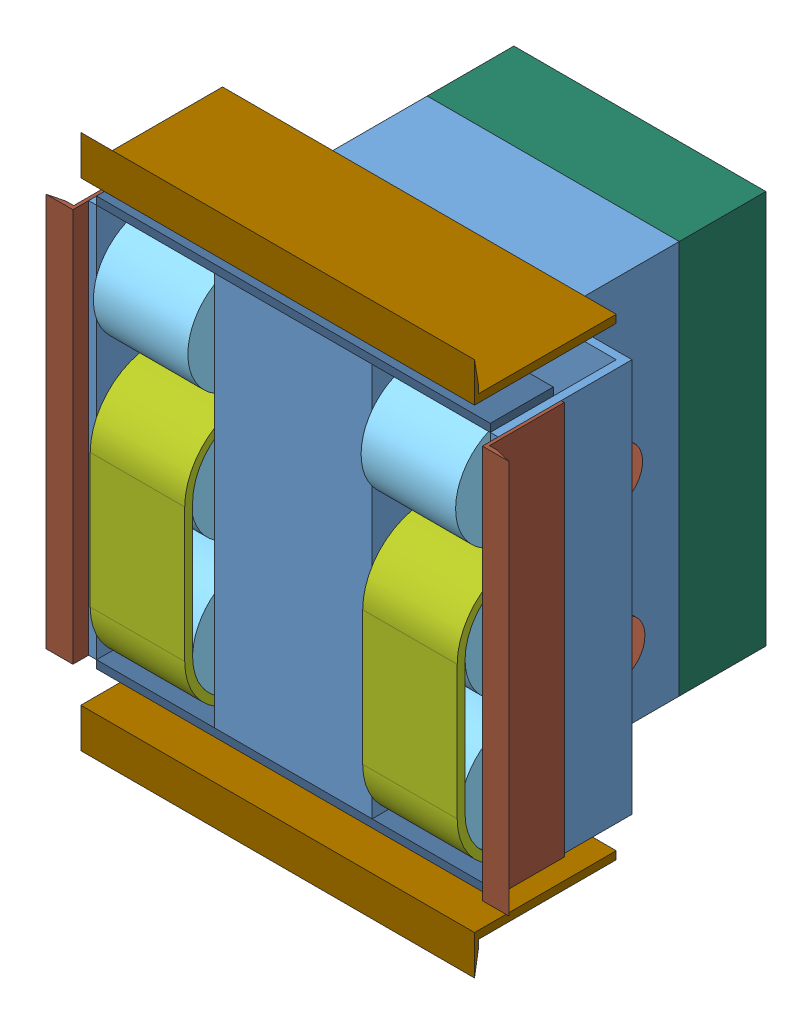
SolidWorks assembly Assemblage2, configuration Défaut. Lengths in mm.
Overall size (294 340 241.57).
35 component instances, 15 part files, 84 mates.
Components (placement in the parent):
- CHASSIS INFERIEUR-1: CHASSIS INFERIEUR [Défaut] at (41.3678 -114.8816 337.5001) size (260 250 165)
- verin-1: verin [Défaut] at (55.5971 35.1184 227.5001) x (0 0 1) z (-1 0 0) size (40 40 135)
- verin-2: verin [Défaut] at (-64.1633 -14.8816 227.5001) x (0 1 0) z (1 0 0) size (40 40 135)
- verin-3: verin [Défaut] at (-62.8283 80.1184 227.5001) x (0 0 -1) z (1 0 0) size (40 40 135)
- verin-4: verin [Défaut] at (57.0896 -59.8816 227.5001) x (0 -1 0) z (-1 0 0) size (40 40 135)
- moteur dc-1: moteur dc [Défaut] at (-28.1322 -92.8521 294.8582) x (-1 0 0) z (0 0.999096 -0.042505) size (44 72 145.16)
- moteur dc-2: moteur dc [Défaut] at (20.8678 112.6401 292.734) x (1 0 0) z (0 -0.999761 -0.021843) size (44 72 145.16)
- axe moteur2-1: axe moteur2 [Défaut] at (-35.6322 10.1184 315.5001) x (0 -0.257747 0.966212) z (-1 0 0) size (15 15 90)
- axe moteur2-2: axe moteur2 [Défaut] at (28.3678 10.1184 315.5001) x (0 -0.997153 0.07541) z (1 0 0) size (15 15 90)
- roue70-1: roue70 [Défaut] at (53.3678 10.1184 315.5001) x (0 0 -1) z (1 0 0) size (70 70 60)
- roue70-2: roue70 [Défaut] at (-60.6322 10.1184 315.5001) x (0 0 1) z (-1 0 0) size (70 70 60)
- axe roues-1: axe roues [Défaut] at (110.3678 -74.8816 315.5001) x (0 0.810625 0.585565) z (-1 0 0) size (15.31 15.16 240)
- roue70-3: roue70 [Défaut] at (-59.6322 -74.8816 315.5001) x (0 0 1) z (-1 0 0) size (70 70 60)
- roue70-4: roue70 [Défaut] at (110.3678 -74.8816 315.5001) x (0 -0.558004 0.829838) z (-1 0 0) size (70 70 60)
- roue70-5: roue70 [Défaut] at (-117.6322 95.1184 320.5001) x (0 0 -1) z (1 0 0) size (70 70 60)
- roue70-6: roue70 [Défaut] at (52.3678 95.1184 320.5001) x (0 -0.261804 -0.965121) z (1 0 0) size (70 70 60)
- axe roues-2: axe roues [Défaut] at (-117.6322 95.1184 320.5001) x (0 -0.953529 0.3013) z (1 0 0) size (15.31 15.16 240)
- courroie-1: courroie [Défaut] at (53.3678 -74.8816 315.5001) x (0 1 0) z (1 0 0) size (165 80 60)
- appuie pare-1: appuie pare [Défaut] at (46.3678 135.1184 297.5001) x (1 0 0) z (0 1 0) size (90 35 20)
- pare avant-1: pare avant [Défaut] at (121.3678 155.1184 352.5001) x (1 0 0) z (0 1 0) size (250 90 25)
- appuie pare-3: appuie pare [Défaut] at (46.3678 -114.8816 262.5001) x (1 0 0) z (0 -1 0) size (90 35 20)
- pare avant-3: pare avant [Défaut] at (-128.6322 -134.8816 352.5001) x (-1 0 0) z (0 -1 0) size (250 90 25)
- suport capteurs-1: suport capteurs [Défaut] at (121.3678 135.1184 342.5001) x (1 0 0) z (0 1 0) size (250 40 5)
- suport capteurs-2: suport capteurs [Défaut] at (121.3678 -119.8816 342.5001) x (1 0 0) z (0 1 0) size (250 40 5)
- pare coté-1: pare coté [Défaut] at (-133.6322 135.1184 352.5001) x (0 1 0) z (-1 0 0) size (250 50 17)
- pare coté-2: pare coté [Défaut] at (126.3678 -114.8816 352.5001) x (0 -1 0) z (1 0 0) size (250 50 17)
- courroie-2: courroie [Défaut] at (-119.6322 -74.8816 315.5001) x (0 1 0) z (1 0 0) size (165 80 60)
- appuie verin-1: appuie verin [Défaut] at (-53.6322 -109.8816 257.5001) x (0 -1 0) z (1 0 0) size (240 110 5)
- appuie verin-2: appuie verin [Défaut] at (46.3678 130.1184 257.5001) x (0 1 0) z (-1 0 0) size (240 110 5)
- chassis superieur-2: chassis superieur [Défaut] at (-83.6322 -114.8816 177.5001) x (-1 0 0) z (0 0 -1) size (160 250 55) (hidden)
- moteur verin-1: moteur verin [Défaut] at (71.3678 37.6184 175.0001) x (0 0.993394 -0.114755) z (-1 0 0) size (25 25 25)
- moteur verin-2: moteur verin [Défaut] at (-78.6322 -17.3816 175.0001) x (0 -0.999164 -0.040883) z (1 0 0) size (25 25 25)
- attache verin-1: attache verin [Défaut] at (-38.6322 -17.8816 174.8001) x (0 -0.190501 -0.981687) z (1 0 0) size (59.09 70.11 25)
- attache verin-2: attache verin [Défaut] at (31.3678 38.1184 174.8001) x (0 0.67748 -0.735541) z (-1 0 0) size (59.09 70.11 25)
- chassis superieur-3: chassis superieur [Défaut] at (-83.6322 -114.8816 177.5001) x (-1 0 0) z (0 0 -1) size (160 250 55)
Mates (geometry in assembly coordinates):
- Coaxiale1: concentric anti-aligned: cylinder of CHASSIS INFERIEUR-1 through (-3.6322 35.1184 227.5001) axis (1 0 0) radius 20; cylinder of verin-1 through (85.5971 35.1184 227.5001) axis (-1 0 0) radius 17.5
- Coaxiale2: concentric anti-aligned: cylinder of CHASSIS INFERIEUR-1 through (-3.6322 -59.8816 227.5001) axis (1 0 0) radius 20; cylinder of verin-4 through (87.0896 -59.8816 227.5001) axis (-1 0 0) radius 17.5
- Coaxiale3: concentric anti-aligned: cylinder of CHASSIS INFERIEUR-1 through (-73.6322 80.1184 227.5001) axis (-1 0 0) radius 20; cylinder of verin-3 through (-92.8283 80.1184 227.5001) axis (1 0 0) radius 17.5
- Coaxiale4: concentric anti-aligned: cylinder of CHASSIS INFERIEUR-1 through (-73.6322 -14.8816 227.5001) axis (-1 0 0) radius 20; cylinder of verin-2 through (-94.1633 -14.8816 227.5001) axis (1 0 0) radius 17.5
- Coïncidente1: coincident aligned: plane of verin-2 through (40.8367 -34.8816 207.5001) normal (0 0 -1); plane of verin-3 through (42.1717 100.1184 207.5001) normal (0 0 -1)
- Coïncidente2: coincident aligned: plane of verin-1 through (-49.4029 55.1184 207.5001) normal (0 0 -1); plane of verin-4 through (-47.9104 -39.8816 207.5001) normal (0 0 -1)
- Coaxiale5: concentric anti-aligned: cylinder of CHASSIS INFERIEUR-1 through (-48.6322 10.1184 315.5001) axis (-1 0 0) radius 10; cylinder of moteur dc-1 through (-45.6322 10.1184 315.5001) axis (1 0 0) radius 5.5
- Coïncidente3: coincident anti-aligned: plane of CHASSIS INFERIEUR-1 through (-48.6322 -114.8816 337.5001) normal (1 0 0); plane of moteur dc-1 through (-48.6322 20.345 298.0594) normal (-1 0 0)
- Coaxiale6: concentric anti-aligned: cylinder of CHASSIS INFERIEUR-1 through (41.3678 10.1184 315.5001) axis (1 0 0) radius 10; cylinder of moteur dc-2 through (38.3678 10.1184 315.5001) axis (-1 0 0) radius 5.5
- Coïncidente4: coincident anti-aligned: plane of CHASSIS INFERIEUR-1 through (41.3678 -114.8816 337.5001) normal (-1 0 0); plane of moteur dc-2 through (41.3678 30.3286 314.946) normal (1 0 0)
- Coaxiale7: concentric aligned: cylinder of moteur dc-1 through (-45.6322 10.1184 315.5001) axis (1 0 0) radius 5.5; cylinder of axe moteur2-1 through (-120.6322 10.1184 315.5001) axis (1 0 0) radius 5
- Coïncidente5: coincident anti-aligned: plane of moteur dc-1 through (-35.6322 -92.8521 294.8582) normal (-1 0 0); plane of axe moteur2-1 through (-35.6322 10.1184 315.5001) normal (1 0 0)
- Coaxiale8: concentric aligned: cylinder of moteur dc-2 through (38.3678 10.1184 315.5001) axis (-1 0 0) radius 5.5; cylinder of axe moteur2-2 through (113.3678 10.1184 315.5001) axis (-1 0 0) radius 5
- Coïncidente6: coincident anti-aligned: plane of moteur dc-2 through (28.3678 112.6401 292.734) normal (1 0 0); plane of axe moteur2-2 through (28.3678 10.1184 315.5001) normal (-1 0 0)
- Coaxiale9: concentric anti-aligned: cylinder of axe moteur2-2 through (113.3678 10.1184 315.5001) axis (-1 0 0) radius 5; cylinder of roue70-1 through (53.3678 10.1184 315.5001) axis (1 0 0) radius 5
- Coïncidente7: coincident anti-aligned: plane of axe moteur2-2 through (113.3678 10.1184 315.5001) normal (-1 0 0); plane of roue70-1 through (113.3678 10.1184 315.5001) normal (1 0 0)
- Coaxiale10: concentric anti-aligned: cylinder of axe moteur2-1 through (-120.6322 10.1184 315.5001) axis (1 0 0) radius 5; cylinder of roue70-2 through (-60.6322 10.1184 315.5001) axis (-1 0 0) radius 5
- Coïncidente8: coincident anti-aligned: plane of axe moteur2-1 through (-120.6322 10.1184 315.5001) normal (1 0 0); plane of roue70-2 through (-120.6322 10.1184 315.5001) normal (-1 0 0)
- Coaxiale11: concentric anti-aligned: cylinder of CHASSIS INFERIEUR-1 through (-48.6322 -74.8816 315.5001) axis (-1 0 0) radius 10; cylinder of axe roues-1 through (-119.6322 -74.8816 315.5001) axis (1 0 0) radius 5
- Distance1: distance = 1 mm anti-aligned: plane of axe roues-1 through (-54.6322 -74.8816 315.5001) normal (1 0 0); plane of CHASSIS INFERIEUR-1 through (-53.6322 -114.8816 337.5001) normal (-1 0 0)
- Coaxiale12: concentric anti-aligned: cylinder of axe roues-1 through (-119.6322 -74.8816 315.5001) axis (1 0 0) radius 5; cylinder of roue70-4 through (110.3678 -74.8816 315.5001) axis (-1 0 0) radius 5
- Coïncidente10: coincident anti-aligned: plane of axe roues-1 through (50.3678 -74.8816 315.5001) normal (1 0 0); plane of roue70-4 through (50.3678 -74.8816 315.5001) normal (-1 0 0)
- Coaxiale13: concentric anti-aligned: cylinder of axe roues-1 through (-119.6322 -74.8816 315.5001) axis (1 0 0) radius 5; cylinder of roue70-3 through (-59.6322 -74.8816 315.5001) axis (-1 0 0) radius 5
- Coïncidente11: coincident anti-aligned: plane of axe roues-1 through (-119.6322 -74.8816 315.5001) normal (1 0 0); plane of roue70-3 through (-119.6322 -74.8816 315.5001) normal (-1 0 0)
- Coaxiale14: concentric anti-aligned: cylinder of CHASSIS INFERIEUR-1 through (41.3678 95.1184 320.5001) axis (1 0 0) radius 10; cylinder of axe roues-2 through (112.3678 95.1184 320.5001) axis (-1 0 0) radius 5
- Distance3: distance = 1 mm anti-aligned: plane of axe roues-2 through (47.3678 95.1184 320.5001) normal (-1 0 0); plane of CHASSIS INFERIEUR-1 through (46.3678 -114.8816 337.5001) normal (1 0 0)
- Coaxiale15: concentric anti-aligned: cylinder of roue70-5 through (-117.6322 95.1184 320.5001) axis (1 0 0) radius 5; cylinder of axe roues-2 through (112.3678 95.1184 320.5001) axis (-1 0 0) radius 5
- Coïncidente14: coincident anti-aligned: plane of roue70-5 through (-117.6322 95.1184 320.5001) normal (-1 0 0); plane of axe roues-2 through (-117.6322 95.1184 320.5001) normal (1 0 0)
- Coaxiale16: concentric anti-aligned: cylinder of roue70-6 through (52.3678 95.1184 320.5001) axis (1 0 0) radius 5; cylinder of axe roues-2 through (112.3678 95.1184 320.5001) axis (-1 0 0) radius 5
- Coïncidente15: coincident anti-aligned: plane of roue70-6 through (52.3678 95.1184 320.5001) normal (-1 0 0); plane of axe roues-2 through (52.3678 95.1184 320.5001) normal (1 0 0)
- Coaxiale17: concentric anti-aligned: cylinder of roue70-4 through (50.3678 -74.8816 315.5001) axis (1 0 0) radius 35; cylinder of courroie-1 through (113.3678 -74.8816 315.5001) axis (-1 0 0) radius 35
- Coaxiale18: concentric aligned: cylinder of roue70-1 through (113.3678 10.1184 315.5001) axis (-1 0 0) radius 35; cylinder of courroie-1 through (113.3678 10.1184 315.5001) axis (-1 0 0) radius 35
- Coïncidente16: coincident aligned: plane of roue70-1 through (113.3678 10.1184 315.5001) normal (1 0 0); plane of courroie-1 through (113.3678 -74.8816 315.5001) normal (1 0 0)
- Coïncidente17: coincident anti-aligned: plane of CHASSIS INFERIEUR-1 through (41.3678 135.1184 342.5001) normal (0 1 0); plane of appuie pare-1 through (46.3678 135.1184 297.5001) normal (0 -1 0)
- Coïncidente18: coincident aligned: plane of CHASSIS INFERIEUR-1 through (46.3678 -114.8816 337.5001) normal (1 0 0); plane of appuie pare-1 through (46.3678 155.1184 297.5001) normal (1 0 0)
- Coïncidente19: coincident anti-aligned: plane of CHASSIS INFERIEUR-1 through (41.3678 -114.8816 262.5001) normal (0 0 1); plane of appuie pare-1 through (46.3678 155.1184 262.5001) normal (0 0 -1)
- Coïncidente20: coincident anti-aligned: plane of appuie pare-1 through (46.3678 155.1184 297.5001) normal (0 1 0); plane of pare avant-1 through (121.3678 155.1184 352.5001) normal (0 -1 0)
- Coïncidente21: coincident aligned: plane of appuie pare-1 through (46.3678 155.1184 262.5001) normal (0 0 -1); plane of pare avant-1 through (121.3678 160.1184 262.5001) normal (0 0 -1)
- Coïncidente22: coincident anti-aligned: plane of CHASSIS INFERIEUR-1 through (121.3678 -114.8816 337.5001) normal (-1 0 0); plane of pare avant-1 through (121.3678 160.1184 352.5001) normal (1 0 0)
- Coïncidente23: coincident anti-aligned: plane of CHASSIS INFERIEUR-1 through (41.3678 -114.8816 342.5001) normal (0 -1 0); plane of appuie pare-3 through (46.3678 -114.8816 262.5001) normal (0 1 0)
- Coïncidente24: coincident anti-aligned: plane of CHASSIS INFERIEUR-1 through (41.3678 -114.8816 262.5001) normal (0 0 1); plane of appuie pare-3 through (46.3678 -134.8816 262.5001) normal (0 0 -1)
- Coïncidente25: coincident aligned: plane of CHASSIS INFERIEUR-1 through (46.3678 -114.8816 337.5001) normal (1 0 0); plane of appuie pare-3 through (46.3678 -134.8816 262.5001) normal (1 0 0)
- Coïncidente26: coincident anti-aligned: plane of appuie pare-3 through (46.3678 -134.8816 262.5001) normal (0 -1 0); plane of pare avant-3 through (-128.6322 -134.8816 352.5001) normal (0 1 0)
- Coïncidente27: coincident aligned: plane of appuie pare-3 through (46.3678 -134.8816 262.5001) normal (0 0 -1); plane of pare avant-3 through (-128.6322 -139.8816 262.5001) normal (0 0 -1)
- Coïncidente28: coincident anti-aligned: plane of CHASSIS INFERIEUR-1 through (-128.6322 -114.8816 337.5001) normal (1 0 0); plane of pare avant-3 through (-128.6322 -139.8816 352.5001) normal (-1 0 0)
- Coïncidente29: coincident anti-aligned: plane of CHASSIS INFERIEUR-1 through (41.3678 135.1184 342.5001) normal (0 1 0); plane of suport capteurs-1 through (121.3678 135.1184 342.5001) normal (0 -1 0)
- Coïncidente30: coincident aligned: plane of CHASSIS INFERIEUR-1 through (41.3678 -114.8816 342.5001) normal (0 0 1); plane of suport capteurs-1 through (121.3678 140.1184 342.5001) normal (0 0 1)
- Coïncidente31: coincident aligned: plane of pare avant-1 through (121.3678 160.1184 352.5001) normal (1 0 0); plane of suport capteurs-1 through (121.3678 140.1184 342.5001) normal (1 0 0)
- Coïncidente32: coincident anti-aligned: plane of CHASSIS INFERIEUR-1 through (41.3678 -114.8816 342.5001) normal (0 -1 0); plane of suport capteurs-2 through (121.3678 -114.8816 342.5001) normal (0 1 0)
- Coïncidente33: coincident aligned: plane of pare avant-3 through (121.3678 -139.8816 352.5001) normal (1 0 0); plane of suport capteurs-2 through (121.3678 -114.8816 342.5001) normal (1 0 0)
- Coïncidente34: coincident aligned: plane of CHASSIS INFERIEUR-1 through (41.3678 -114.8816 342.5001) normal (0 0 1); plane of suport capteurs-2 through (121.3678 -114.8816 342.5001) normal (0 0 1)
- Coïncidente35: coincident anti-aligned: plane of CHASSIS INFERIEUR-1 through (126.3678 -114.8816 337.5001) normal (1 0 0); plane of pare coté-2 through (126.3678 -114.8816 352.5001) normal (-1 0 0)
- Coïncidente36: coincident aligned: plane of pare avant-1 through (121.3678 160.1184 352.5001) normal (0 0 1); plane of pare coté-2 through (128.3678 -114.8816 352.5001) normal (0 0 1)
- Coïncidente37: coincident aligned: plane of CHASSIS INFERIEUR-1 through (41.3678 -114.8816 342.5001) normal (0 -1 0); plane of pare coté-2 through (128.3678 -114.8816 352.5001) normal (0 -1 0)
- Coïncidente38: coincident anti-aligned: plane of CHASSIS INFERIEUR-1 through (-133.6322 -114.8816 337.5001) normal (-1 0 0); plane of pare coté-1 through (-133.6322 135.1184 352.5001) normal (1 0 0)
- Coïncidente39: coincident aligned: plane of pare avant-3 through (-128.6322 -139.8816 352.5001) normal (0 0 1); plane of pare coté-1 through (-135.6322 135.1184 352.5001) normal (0 0 1)
- Coïncidente40: coincident aligned: plane of CHASSIS INFERIEUR-1 through (41.3678 -114.8816 342.5001) normal (0 -1 0); plane of pare coté-1 through (-135.6322 -114.8816 352.5001) normal (0 -1 0)
- Coaxiale19: concentric anti-aligned: cylinder of roue70-2 through (-120.6322 10.1184 315.5001) axis (1 0 0) radius 35; cylinder of courroie-2 through (-59.6322 10.1184 315.5001) axis (-1 0 0) radius 35
- Coaxiale20: concentric anti-aligned: cylinder of roue70-3 through (-119.6322 -74.8816 315.5001) axis (1 0 0) radius 35; cylinder of courroie-2 through (-59.6322 -74.8816 315.5001) axis (-1 0 0) radius 35
- Coïncidente41: coincident aligned: plane of roue70-3 through (-119.6322 -74.8816 315.5001) normal (-1 0 0); plane of courroie-2 through (-119.6322 -74.8816 315.5001) normal (-1 0 0)
- Parallèle1: parallel anti-aligned: plane of CHASSIS INFERIEUR-1 through (-78.6322 135.1184 177.5001) normal (1 0 0); plane of appuie verin-1 through (-53.6322 -109.8816 257.5001) normal (-1 0 0)
- Coïncidente47: coincident anti-aligned: plane of CHASSIS INFERIEUR-1 through (41.3678 -109.8816 337.5001) normal (0 1 0); plane of appuie verin-1 through (-48.6322 -109.8816 257.5001) normal (0 -1 0)
- Parallèle3: parallel anti-aligned: plane of CHASSIS INFERIEUR-1 through (71.3678 135.1184 177.5001) normal (-1 0 0); plane of appuie verin-2 through (46.3678 130.1184 257.5001) normal (1 0 0)
- Coïncidente51: coincident anti-aligned: plane of CHASSIS INFERIEUR-1 through (41.3678 -109.8816 337.5001) normal (0 1 0); plane of appuie verin-2 through (41.3678 -109.8816 257.5001) normal (0 -1 0)
- Coïncidente52: coincident aligned: plane of CHASSIS INFERIEUR-1 through (41.3678 -114.8816 337.5001) normal (-1 0 0); plane of appuie verin-2 through (41.3678 130.1184 257.5001) normal (-1 0 0)
- Coïncidente53: coincident anti-aligned: plane of CHASSIS INFERIEUR-1 through (41.3678 -114.8816 257.5001) normal (0 0 -1); plane of appuie verin-2 through (41.3678 130.1184 257.5001) normal (0 0 1)
- Coïncidente56: coincident anti-aligned: plane of CHASSIS INFERIEUR-1 through (-48.6322 -114.8816 257.5001) normal (0 0 -1); plane of appuie verin-1 through (-48.6322 -109.8816 257.5001) normal (0 0 1)
- Coïncidente58: coincident anti-aligned: plane of CHASSIS INFERIEUR-1 through (41.3678 -114.8816 177.5001) normal (0 0 -1); plane of chassis superieur-2 through (-83.6322 -114.8816 177.5001) normal (0 0 1)
- Coïncidente59: coincident aligned: plane of CHASSIS INFERIEUR-1 through (76.3678 135.1184 177.5001) normal (1 0 0); plane of chassis superieur-2 through (76.3678 -114.8816 127.5001) normal (1 0 0)
- Coïncidente60: coincident aligned: plane of CHASSIS INFERIEUR-1 through (41.3678 -114.8816 342.5001) normal (0 -1 0); plane of chassis superieur-2 through (-83.6322 -114.8816 127.5001) normal (0 -1 0)
- Coïncidente61: coincident aligned: plane of CHASSIS INFERIEUR-1 through (-48.6322 -114.8816 337.5001) normal (1 0 0); plane of appuie verin-1 through (-48.6322 -109.8816 257.5001) normal (1 0 0)
- Coïncidente62: coincident anti-aligned: plane of CHASSIS INFERIEUR-1 through (-78.6322 135.1184 177.5001) normal (1 0 0); plane of moteur verin-2 through (-78.6322 -17.3816 175.0001) normal (-1 0 0)
- Coïncidente63: coincident anti-aligned: plane of CHASSIS INFERIEUR-1 through (71.3678 135.1184 177.5001) normal (-1 0 0); plane of moteur verin-1 through (71.3678 37.6184 175.0001) normal (1 0 0)
- Distance10: distance = 80 mm anti-aligned: cylinder of moteur verin-1 through (46.3678 37.6184 175.0001) axis (1 0 0) radius 12.5; plane of CHASSIS INFERIEUR-1 through (41.3678 130.1184 337.5001) normal (0 -1 0)
- Distance11: distance = 70 mm anti-aligned: cylinder of moteur verin-1 through (46.3678 37.6184 175.0001) axis (1 0 0) radius 12.5; plane of CHASSIS INFERIEUR-1 through (41.3678 -114.8816 257.5001) normal (0 0 -1)
- Distance12: distance = 80 mm anti-aligned: cylinder of moteur verin-2 through (-53.6322 -17.3816 175.0001) axis (-1 0 0) radius 12.5; plane of CHASSIS INFERIEUR-1 through (41.3678 -109.8816 337.5001) normal (0 1 0)
- Distance13: distance = 70 mm anti-aligned: cylinder of moteur verin-2 through (-53.6322 -17.3816 175.0001) axis (-1 0 0) radius 12.5; plane of CHASSIS INFERIEUR-1 through (-48.6322 -114.8816 257.5001) normal (0 0 -1)
- Coaxiale29: concentric aligned: cylinder of appuie verin-1 through (-53.6322 -17.8816 174.8001) axis (1 0 0) radius 5; cylinder of attache verin-1 through (-58.6322 -17.8816 174.8001) axis (1 0 0) radius 5
- Coïncidente64: coincident anti-aligned: plane of moteur verin-2 through (-58.6322 -17.3816 175.0001) normal (1 0 0); plane of attache verin-1 through (-58.6322 -17.8816 174.8001) normal (-1 0 0)
- Coaxiale30: concentric aligned: cylinder of appuie verin-2 through (46.3678 38.1184 174.8001) axis (-1 0 0) radius 5; cylinder of attache verin-2 through (51.3678 38.1184 174.8001) axis (-1 0 0) radius 5
- Coïncidente65: coincident anti-aligned: plane of moteur verin-1 through (51.3678 37.6184 175.0001) normal (-1 0 0); plane of attache verin-2 through (51.3678 38.1184 174.8001) normal (1 0 0)
- Coïncidente66: coincident anti-aligned: plane of CHASSIS INFERIEUR-1 through (41.3678 -114.8816 177.5001) normal (0 0 -1); plane of chassis superieur-3 through (-83.6322 -114.8816 177.5001) normal (0 0 1)
- Coïncidente67: coincident aligned: plane of CHASSIS INFERIEUR-1 through (-83.6322 135.1184 177.5001) normal (-1 0 0); plane of chassis superieur-3 through (-83.6322 -114.8816 127.5001) normal (-1 0 0)
- Coïncidente68: coincident aligned: plane of CHASSIS INFERIEUR-1 through (41.3678 -114.8816 342.5001) normal (0 -1 0); plane of chassis superieur-3 through (-83.6322 -114.8816 127.5001) normal (0 -1 0)
